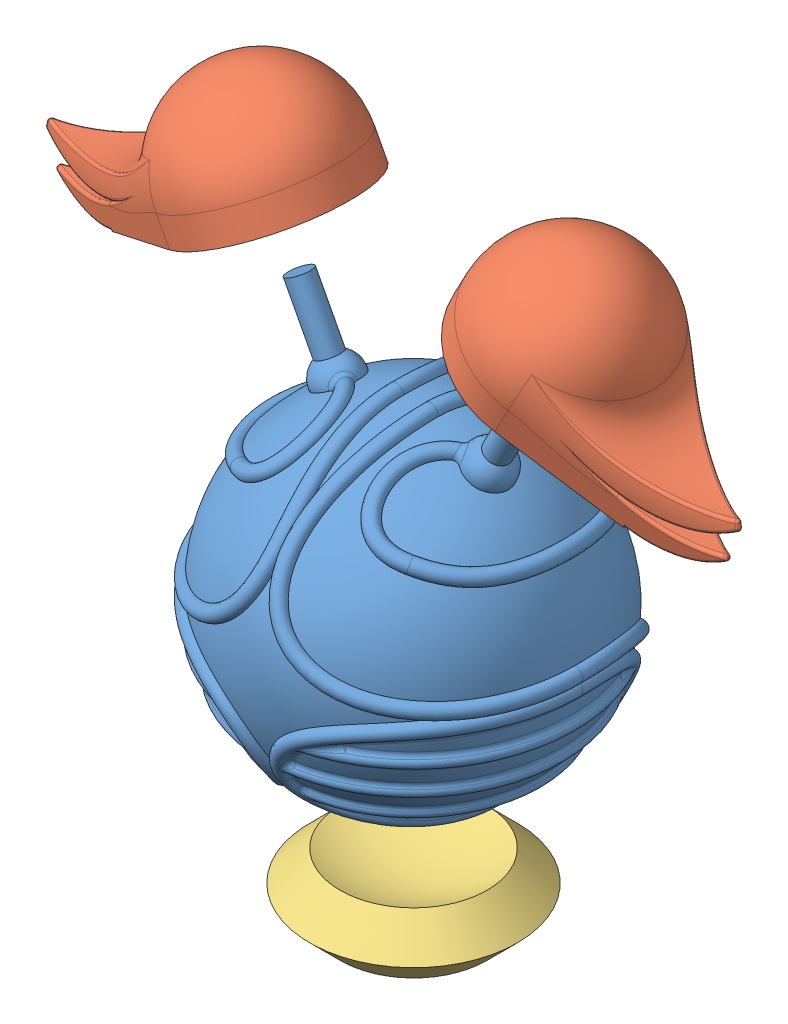
SolidWorks assembly Snitch Clock Exploded Assembly, configuration Default. Lengths in mm.
Overall size (390.97 347.98 194.3).
4 component instances, 3 part files, 4 mates.
Components (placement in the parent):
- Snitch Clock-2: Snitch Clock [Default] at (43.137 109.2453 141.7651) size (169.18 189.84 147.07)
- Snitch Bell-1: Snitch Bell [Default] at (-30.6389 243.4025 141.9799) x (0.881883 0.46481 -0.07895) z (0.069843 0.036812 0.996879) size (146.75 58.57 177.29)
- Snitch Bell-2: Snitch Bell [Default] at (118.0924 245.6683 142.1064) x (-0.87766 0.462584 -0.125412) z (0.110945 -0.058475 -0.992105) size (146.75 58.57 177.29)
- Electromagnetic Base-1: Electromagnetic Base [Default] at (43.137 -32.1518 141.7651) x (0.986329 0 0.164788) z (-0.164788 0 0.986329) size (102.46 30 102.46)
Mates (geometry in assembly coordinates):
- Concentric1: concentric anti-aligned: cylinder of snitch clock (2)-2 through (5.3695 180.9015 141.7651) axis (-0.466266 0.884645 0) radius 6; cylinder of Snitch Bell-1 through (-38.5296 264.1913 141.7651) axis (0.466266 -0.884645 0) radius 6
- Concentric2: concentric anti-aligned: cylinder of snitch clock (2)-2 through (80.9045 180.9015 141.7651) axis (0.466266 0.884645 0) radius 6; cylinder of Snitch Bell-2 through (125.9947 266.4509 141.7651) axis (-0.466266 -0.884645 0) radius 6
- Coincident3: coincident anti-aligned: line of Snitch Clock-2 through (43.137 108.9582 141.7651) axis (0 -1 0); line of Electromagnetic Base-1 through (43.137 -27.0548 141.7651) axis (0 1 0)
- Distance4: distance = 40 mm aligned: sphere of Electromagnetic Base-1; sphere of Snitch Clock-2
